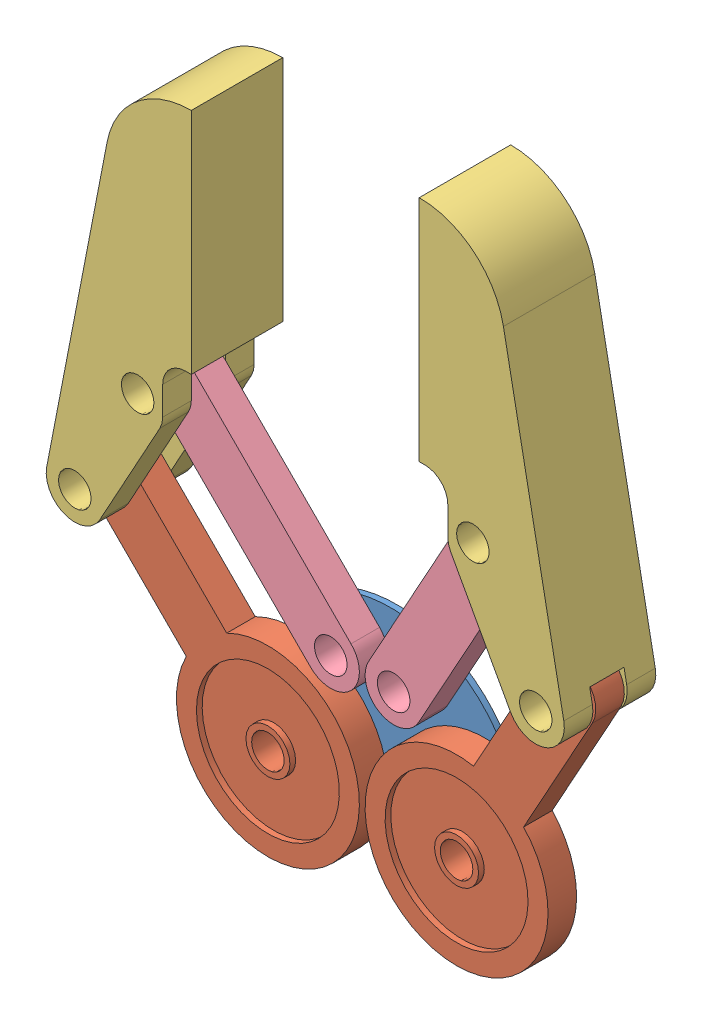
SolidWorks assembly Claw1, configuration Default. Lengths in mm.
Overall size (131.9 125.22 41.99).
7 component instances, 4 part files, 18 mates.
Components (placement in the parent):
- Arm_Plate-1: Arm_Plate [Default] at (16.3184 9.8304 30.4902) x (0 -1 0) z (0 0 1) size (32.5 45 1)
- Arm_Gear-1: Arm_Gear [Default] at (-14.3238 23.9725 33.9902) x (0.707107 -0.707107 0) z (0 0 1) size (61 32 5)
- Grip-1: Grip [Default] at (31.79 112.4275 25.9902) x (0 -1 0) z (0 0 1) size (72.59 25.38 16)
- Arm_Link-3: Arm_Link [Default] at (-3.3238 43.9725 33.9902) x (-0.707107 0.707107 0) z (0 0 1) size (50 10 5)
- Arm_Gear-2: Arm_Gear [Default] at (42.4948 27.3338 33.9902) x (-0.483819 -0.875168 0) z (0 0 1) size (61 32 5)
- Grip-3: Grip [Default] at (-8.0848 105.7051 41.9902) x (0 -1 0) z (0 0 -1) size (72.59 25.38 16)
- Arm_Link-4: Arm_Link [Default] at (31.4948 47.3338 33.9902) x (-0.483819 -0.875168 0) z (0 0 1) size (50 10 5)
Mates (geometry in assembly coordinates):
- Concentric1: concentric aligned: cylinder of Arm_Plate-1 through (-0.1816 9.8304 31.4902) axis (0 0 -1) radius 2.85; cylinder of Arm_Gear-1 through (-0.1816 9.8304 36.4902) axis (0 0 -1) radius 2.85
- Concentric2: concentric aligned: cylinder of Arm_Plate-1 through (32.8184 9.8304 31.4902) axis (0 0 -1) radius 2.85; cylinder of Arm_Gear-2 through (32.8184 9.8304 36.4902) axis (0 0 -1) radius 2.85
- Concentric3: concentric aligned: cylinder of Grip-1 through (52.1711 44.8371 41.9902) axis (0 0 -1) radius 2.85; cylinder of Arm_Gear-2 through (52.1711 44.8371 36.4902) axis (0 0 -1) radius 2.85
- Concentric4: concentric anti-aligned: cylinder of Arm_Gear-1 through (-28.4659 38.1147 36.4902) axis (0 0 -1) radius 2.85; cylinder of Grip-3 through (-28.4659 38.1147 25.9902) axis (0 0 1) radius 2.85
- Concentric5: concentric aligned: cylinder of Arm_Plate-1 through (10.8184 29.8304 31.4902) axis (0 0 -1) radius 2.85; cylinder of Arm_Link-3 through (10.8184 29.8304 36.4902) axis (0 0 -1) radius 2.85
- Concentric6: concentric aligned: cylinder of Arm_Plate-1 through (21.8184 29.8304 31.4902) axis (0 0 -1) radius 2.85; cylinder of Arm_Link-4 through (21.8184 29.8304 36.4902) axis (0 0 -1) radius 2.85
- Concentric7: concentric aligned: cylinder of Grip-1 through (41.1711 64.8371 41.9902) axis (0 0 -1) radius 2.85; cylinder of Arm_Link-4 through (41.1711 64.8371 36.4902) axis (0 0 -1) radius 2.85
- Concentric8: concentric anti-aligned: cylinder of Arm_Link-3 through (-17.4659 58.1147 36.4902) axis (0 0 -1) radius 2.85; cylinder of Grip-3 through (-17.4659 58.1147 36.9902) axis (0 0 1) radius 2.85
- Width1: width anti-aligned: plane of Grip-1 through (32.79 68.4275 30.9902) normal (0 0 1); plane of Grip-1 through (94.5973 39.8371 36.9902) normal (0 0 -1); plane of Arm_Link-4 through (41.1711 64.8371 31.4902) normal (0 0 -1); plane of Arm_Link-4 through (41.1711 64.8371 36.4902) normal (0 0 1)
- Width2: width anti-aligned: plane of Arm_Link-3 through (10.8184 29.8304 31.4902) normal (0 0 -1); plane of Arm_Link-3 through (10.8184 29.8304 36.4902) normal (0 0 1); plane of Grip-3 through (-70.8921 33.1147 30.9902) normal (0 0 1); plane of Grip-3 through (-9.0848 61.7051 36.9902) normal (0 0 -1)
- Width3: width anti-aligned: plane of Arm_Gear-1 through (-28.4659 38.1147 36.4902) normal (0 0 1); plane of Arm_Gear-1 through (-28.4659 38.1147 31.4902) normal (0 0 -1); plane of Grip-3 through (-9.0848 61.7051 36.9902) normal (0 0 -1); plane of Grip-3 through (-70.8921 33.1147 30.9902) normal (0 0 1)
- Width4: width anti-aligned: plane of Grip-1 through (32.79 68.4275 30.9902) normal (0 0 1); plane of Grip-1 through (94.5973 39.8371 36.9902) normal (0 0 -1); plane of Arm_Gear-2 through (52.1711 44.8371 31.4902) normal (0 0 -1); plane of Arm_Gear-2 through (52.1711 44.8371 36.4902) normal (0 0 1)
- Coincident3: coincident aligned: plane of Grip-1 through (31.79 97.4275 41.9902) normal (0 0 1); plane of Grip-3 through (-8.0848 90.7051 41.9902) normal (0 0 1)
- Coincident4: coincident anti-aligned: plane of Arm_Plate-1 through (16.3184 14.8304 31.4902) normal (0 0 1); plane of Arm_Link-4 through (41.1711 64.8371 31.4902) normal (0 0 -1)
- Angle1: planar angle = 0.785398 rad anti-aligned: plane of assembly through (0 0 0) normal (0 1 0); plane of Arm_Gear-1 through (-32.0014 34.5791 36.4902) normal (-0.707107 -0.707107 0)
- GearMate1: gear = 32 : 54 mm: cylinder of Arm_Gear-2 through (32.8184 9.8304 36.4902) axis (0 0 -1) radius 16; cylinder of Arm_Gear-1 through (-0.1816 9.8304 36.4902) axis (0 0 -1) radius 16
- Coincident5: coincident anti-aligned: plane of Grip-1 through (16.3184 117.2321 41.9902) normal (-1 0 0); plane of Grip-3 through (16.3184 117.2321 25.9902) normal (1 0 0)
- Concentric9: concentric anti-aligned: cylinder of Grip-1 through (16.3184 102.2321 41.9902) axis (0 0 -1) radius 15; cylinder of Grip-3 through (16.3184 102.2321 25.9902) axis (0 0 1) radius 15
